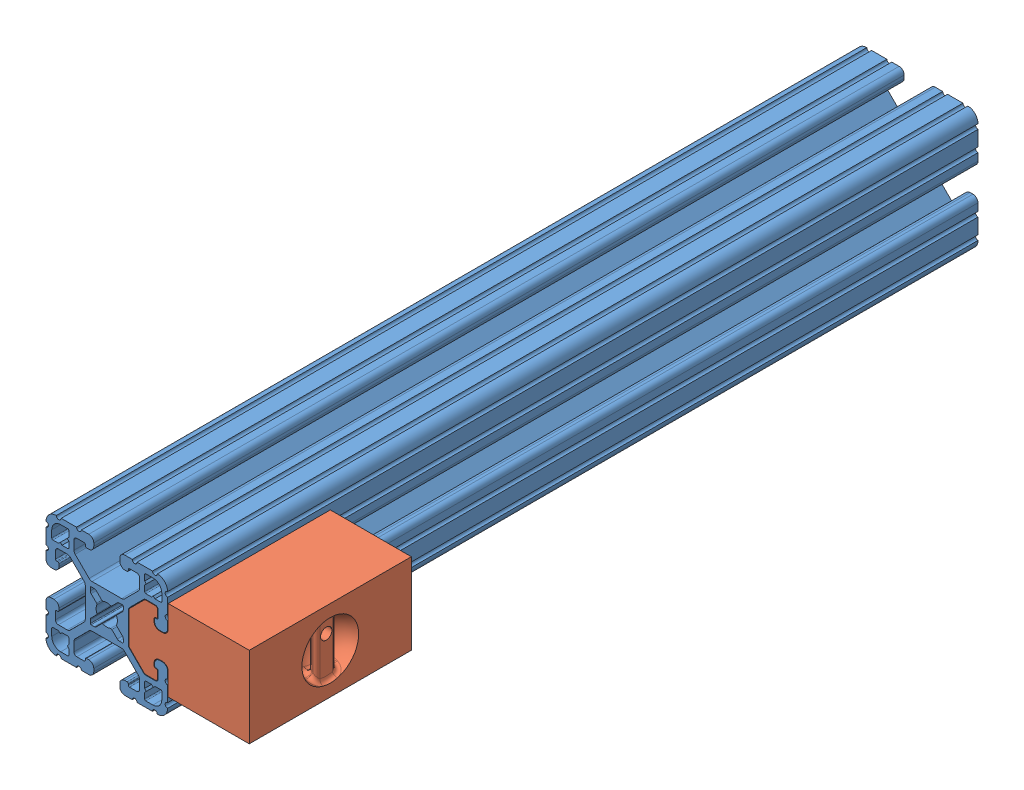
SolidWorks assembly TslotAttachmentAssem, configuration Default. Lengths in mm.
Overall size (70.3 41.91 254).
2 component instances, 2 part files, 4 mates.
Components (placement in the parent):
- 8020- 1515-UL X 145_10in-1: 8020- 1515-UL X 145_10in [Default] at (-12.0883 110.7846 266.1641) size (38.1 38.1 254)
- Part1^TslotAttachmentAssem-1: Part1^TslotAttachmentAssem [Default] at (-12.0883 110.7846 266.1641) size (37.94 25.4 50.8) (virtual)
Mates (geometry in assembly coordinates):
- InPlace1: in place: plane of ? through (-5.7383 95.4187 266.1641) normal (0 0 1); plane of ? through (0 0 266.1641) normal (0 0 1); moOrthogonalPlaneRef_w of ? through (-5.7383 95.4187 266.1641) normal (0 0 1); plane of ? through (0 0 266.1641) normal (0 1 0); plane of ? through (-5.7383 95.4187 266.1641) normal (0 0 1); plane of ? through (0 0 266.1641) normal (1 0 0); plane of ? through (-5.7383 95.4187 266.1641) normal (0 0 1); unknown of ?
- Coincident1: coincident aligned: plane of 8020- 1515-UL X 145_10in-1; plane of Part1^TslotAttachmentAssem-1
- Coincident2: coincident aligned: moOrthogonalPlaneRef_w of 8020- 1515-UL X 145_10in-1 through (-12.0883 110.7846 266.1641) normal (0 1 0); plane of Part1^TslotAttachmentAssem-1 through (-12.0883 110.7846 266.1641) normal (0 1 0)
- Coincident3: coincident anti-aligned: moOrthogonalPlaneRef_w of 8020- 1515-UL X 145_10in-1 through (-12.0883 110.7846 266.1641) normal (-1 0 0); plane of Part1^TslotAttachmentAssem-1 through (-12.0883 110.7846 266.1641) normal (1 0 0)
